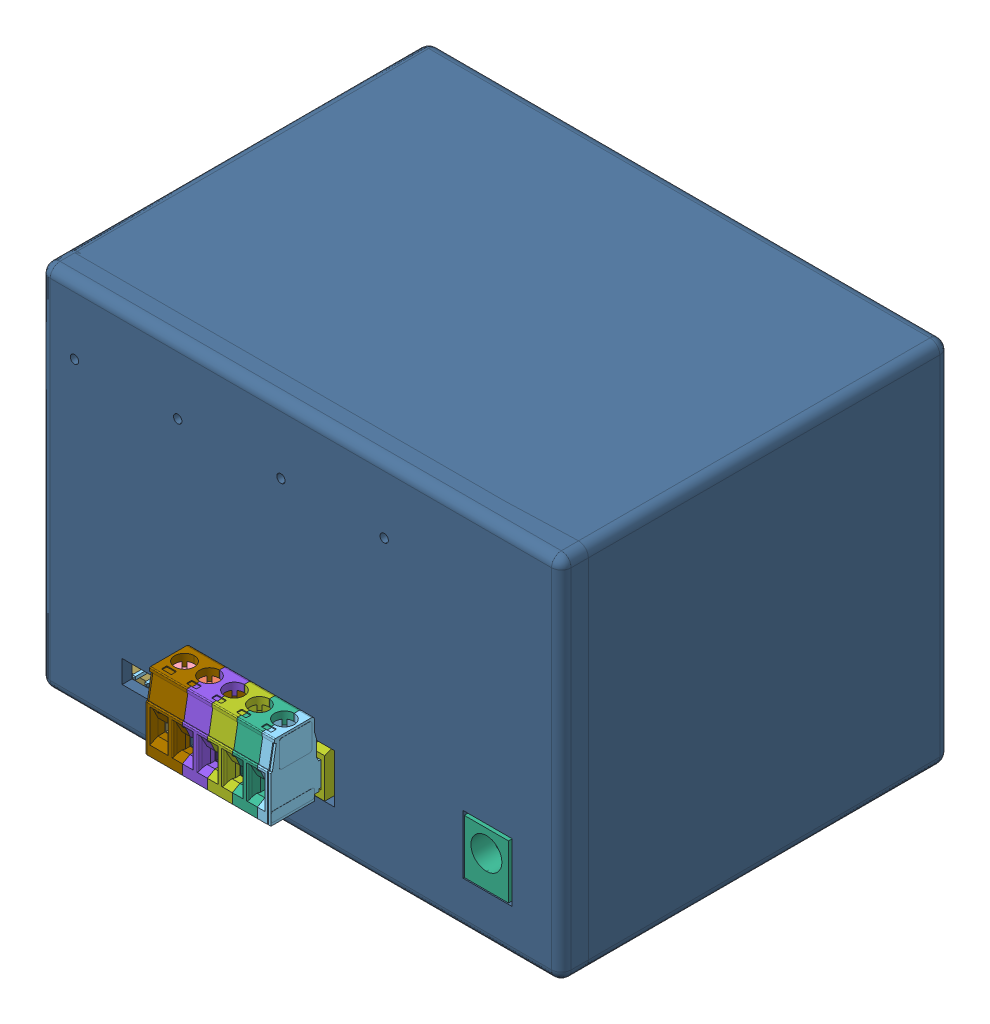
SolidWorks assembly scbs_array_enclosed_assy, configuration Default. Lengths in mm.
Overall size (106 74.85 90.17).
81 component instances, 28 part files, 2 mates.
Components (placement in the parent):
- scbs_array_pcba-1: scbs_array_pcba [Default] at (-110 -62.35 -69.591) x (1 0 0) z (0 1 0) size (91.35 87.17 67.03)
  - PinSocket_1x06_P2.54mm_Vertical-1: PinSocket_1x06_P2.54mm_Vertical [PinSocket_1x06_P2.54mm_Vertical] at (47 -65 1.65) size (2.54 15.24 10.1)
    - SOLID-1: SOLID [SOLID] at origin size (2.54 15.24 10.1)
  - scbs_pico-1: scbs_pico [scbs_pico] at (45.7 -102.3 87.35) x (0 0 -1) z (-1 0 0) size (60 60 13.4)
    - COMPOUND-1: COMPOUND [COMPOUND] at origin size (60 60 13.4)
  - Converter_DCDC_TRACO_TMR-xxxx_THT-1: Converter_DCDC_TRACO_TMR-xxxx_THT [Converter_DCDC_TRACO_TMR-xxxx_THT] at (33 -33 1.65) x (0 -1 0) z (0 0 1) size (21.8 9.2 15)
    - SOLID-0-1: SOLID-0 [SOLID-0] at origin size (21.8 9.2 15)
  - CP_Radial_D5.0mm_P2.50mm-1: CP_Radial_D5.0mm_P2.50mm [CP_Radial_D5.0mm_P2.50mm] at (61 -46 1.65) x (0 -1 0) z (0 0 1) size (6.13 6.52 7)
    - SOLID-1-1: SOLID-1 [SOLID-1] at origin size (6.13 6.52 7)
  - CP_Radial_D5.0mm_P2.50mm-2: CP_Radial_D5.0mm_P2.50mm [CP_Radial_D5.0mm_P2.50mm] at (103.5 -46 1.65) x (0 -1 0) z (0 0 1) size (6.13 6.52 7)
    - SOLID-1-1: SOLID-1 [SOLID-1] at origin size (6.13 6.52 7)
  - PinHeader_1x03_P2.54mm_Horizontal-1: PinHeader_1x03_P2.54mm_Horizontal [PinHeader_1x03_P2.54mm_Horizontal] at (36 -86 1.65) x (0 -1 0) z (0 0 1) size (10.36 7.62 5.54)
    - SOLID-2-1: SOLID-2 [SOLID-2] at origin size (10.36 7.62 5.54)
  - CP_Radial_D5.0mm_P2.50mm-3: CP_Radial_D5.0mm_P2.50mm [CP_Radial_D5.0mm_P2.50mm] at (61 -36 1.65) x (0 1 0) z (0 0 1) size (6.13 6.52 7)
    - SOLID-1-1: SOLID-1 [SOLID-1] at origin size (6.13 6.52 7)
  - CP_Radial_D5.0mm_P2.50mm-4: CP_Radial_D5.0mm_P2.50mm [CP_Radial_D5.0mm_P2.50mm] at (82 -46 1.65) x (0 -1 0) z (0 0 1) size (6.13 6.52 7)
    - SOLID-1-1: SOLID-1 [SOLID-1] at origin size (6.13 6.52 7)
  - Converter_DCDC_TRACO_TMR-xxxx_THT-2: Converter_DCDC_TRACO_TMR-xxxx_THT [Converter_DCDC_TRACO_TMR-xxxx_THT] at (96.5 -33 1.65) x (0 -1 0) z (0 0 1) size (21.8 9.2 15)
    - SOLID-0-1: SOLID-0 [SOLID-0] at origin size (21.8 9.2 15)
  - CP_Radial_D5.0mm_P2.50mm-5: CP_Radial_D5.0mm_P2.50mm [CP_Radial_D5.0mm_P2.50mm] at (40 -36 1.65) x (0 1 0) z (0 0 1) size (6.13 6.52 7)
    - SOLID-1-1: SOLID-1 [SOLID-1] at origin size (6.13 6.52 7)
  - SOFNG_DC005-T20-1: SOFNG_DC005-T20 [SOFNG_DC005-T20] at (103 -89 1.65) x (0 -1 0) z (-1 0 0) size (14.5 15.45 9.3)
    - COMPOUND-3-1: COMPOUND-3 [COMPOUND-3] at origin size (14.5 15.45 9.3)
  - PinSocket_1x06_P2.54mm_Vertical-2: PinSocket_1x06_P2.54mm_Vertical [PinSocket_1x06_P2.54mm_Vertical] at (68 -65 1.65) size (2.54 15.24 10.1)
    - SOLID-1: SOLID [SOLID] at origin size (2.54 15.24 10.1)
  - scbs_pico-2: scbs_pico [scbs_pico] at (66.7 -102.3 87.35) x (0 0 -1) z (-1 0 0) size (60 60 13.4)
    - COMPOUND-1: COMPOUND [COMPOUND] at origin size (60 60 13.4)
  - PhoenixContact_MSTBA_2,5_5-G-5,08_1x05_P5.08mm_Horizontal-1: PhoenixContact_MSTBA_2,5_5-G-5,08_1x05_P5.08mm_Horizontal [PhoenixContact_MSTBA_2,5_5-G-5,08_1x05_P5.08mm_Horizontal] at (47 -87 1.65) size (27.4 12 12.6)
    - SOLID-4-1: SOLID-4 [SOLID-4] at origin size (27.4 12 12.6)
  - PinSocket_1x06_P2.54mm_Vertical-3: PinSocket_1x06_P2.54mm_Vertical [PinSocket_1x06_P2.54mm_Vertical] at (26 -65 1.65) size (2.54 15.24 10.1)
    - SOLID-1: SOLID [SOLID] at origin size (2.54 15.24 10.1)
  - scbs_pico-3: scbs_pico [scbs_pico] at (24.7 -102.3 87.35) x (0 0 -1) z (-1 0 0) size (60 60 13.4)
    - COMPOUND-1: COMPOUND [COMPOUND] at origin size (60 60 13.4)
  - Converter_DCDC_TRACO_TMR-xxxx_THT-3: Converter_DCDC_TRACO_TMR-xxxx_THT [Converter_DCDC_TRACO_TMR-xxxx_THT] at (54 -33 1.65) x (0 -1 0) z (0 0 1) size (21.8 9.2 15)
    - SOLID-0-1: SOLID-0 [SOLID-0] at origin size (21.8 9.2 15)
  - CP_Radial_D5.0mm_P2.50mm-6: CP_Radial_D5.0mm_P2.50mm [CP_Radial_D5.0mm_P2.50mm] at (40 -46 1.65) x (0 -1 0) z (0 0 1) size (6.13 6.52 7)
    - SOLID-1-1: SOLID-1 [SOLID-1] at origin size (6.13 6.52 7)
  - PinSocket_1x06_P2.54mm_Vertical-4: PinSocket_1x06_P2.54mm_Vertical [PinSocket_1x06_P2.54mm_Vertical] at (89 -65 1.65) size (2.54 15.24 10.1)
    - SOLID-1: SOLID [SOLID] at origin size (2.54 15.24 10.1)
  - scbs_pico-4: scbs_pico [scbs_pico] at (87.7 -102.3 87.35) x (0 0 -1) z (-1 0 0) size (60 60 13.4)
    - COMPOUND-1: COMPOUND [COMPOUND] at origin size (60 60 13.4)
  - TO-220-3_Horizontal_TabDown-1: TO-220-3_Horizontal_TabDown [TO-220-3_Horizontal_TabDown] at (101 -78 1.65) size (10.25 19.74 10.78)
    - SOLID-5-1: SOLID-5 [SOLID-5] at origin size (10.25 19.74 10.78)
  - CP_Radial_D5.0mm_P2.50mm-7: CP_Radial_D5.0mm_P2.50mm [CP_Radial_D5.0mm_P2.50mm] at (82 -36 1.65) x (0 1 0) z (0 0 1) size (6.13 6.52 7)
    - SOLID-1-1: SOLID-1 [SOLID-1] at origin size (6.13 6.52 7)
  - Converter_DCDC_TRACO_TMR-xxxx_THT-4: Converter_DCDC_TRACO_TMR-xxxx_THT [Converter_DCDC_TRACO_TMR-xxxx_THT] at (75 -33 1.65) x (0 -1 0) z (0 0 1) size (21.8 9.2 15)
    - SOLID-0-1: SOLID-0 [SOLID-0] at origin size (21.8 9.2 15)
  - CP_Radial_D5.0mm_P2.50mm-8: CP_Radial_D5.0mm_P2.50mm [CP_Radial_D5.0mm_P2.50mm] at (103.5 -36 1.65) x (0 1 0) z (0 0 1) size (6.13 6.52 7)
    - SOLID-1-1: SOLID-1 [SOLID-1] at origin size (6.13 6.52 7)
  - R_0805_2012Metric-1: R_0805_2012Metric [R_0805_2012Metric] at (98 -70 -0.05) x (-1 0 0) z (0 0 -1) size (2 1.2 0.45)
    - SOLID-6-1: SOLID-6 [SOLID-6] at origin size (2 1.2 0.45)
  - C_0805_2012Metric-1: C_0805_2012Metric [C_0805_2012Metric] at (71 -50 -0.05) x (0 1 0) z (0 0 -1) size (2 1.25 1.25)
    - SOLID-7-1: SOLID-7 [SOLID-7] at origin size (2 1.25 1.25)
  - D_MELF-1: D_MELF [D_MELF] at (103.54 -73.77 -0.05) x (-1 0 0) z (0 0 -1) size (5.8 2.2 2.2)
    - SOLID-8-1: SOLID-8 [SOLID-8] at origin size (5.8 2.2 2.2)
  - C_0805_2012Metric-2: C_0805_2012Metric [C_0805_2012Metric] at (49.4 -50 -0.05) x (0 1 0) z (0 0 -1) size (2 1.25 1.25)
    - SOLID-7-1: SOLID-7 [SOLID-7] at origin size (2 1.25 1.25)
  - R_0805_2012Metric-2: R_0805_2012Metric [R_0805_2012Metric] at (94 -70 -0.05) x (0 1 0) z (0 0 -1) size (2 1.2 0.45)
    - SOLID-6-1: SOLID-6 [SOLID-6] at origin size (2 1.2 0.45)
  - C_0805_2012Metric-3: C_0805_2012Metric [C_0805_2012Metric] at (29 -50 -0.05) x (0 1 0) z (0 0 -1) size (2 1.25 1.25)
    - SOLID-7-1: SOLID-7 [SOLID-7] at origin size (2 1.25 1.25)
  - C_0805_2012Metric-4: C_0805_2012Metric [C_0805_2012Metric] at (92.5 -50 -0.05) x (0 1 0) z (0 0 -1) size (2 1.25 1.25)
    - SOLID-7-1: SOLID-7 [SOLID-7] at origin size (2 1.25 1.25)
  - scbs_array PCB-1: scbs_array PCB [scbs_array PCB] at origin size (90 74 1.6)
  - pxc_1757048_06_MSTB-2-5-5-ST-5-08_3D-1: pxc_1757048_06_MSTB-2-5-5-ST-5-08_3D [pxc_1757048_06_MSTB-2-5-5-ST-5-08_3D] at (44.46 -106.94 1.705) size (25.46 18.3 15)
    - 2022_06_08_09_32_02_0871-1: 2022_06_08_09_32_02_0871 [2022_06_08_09_32_02_0871] at origin size (3.8 5 6.8)
    - 2022_06_08_09_32_02_0840-1: 2022_06_08_09_32_02_0840 [2022_06_08_09_32_02_0840] at origin size (3.82 3.82 6.8)
    - 2022_06_08_09_32_02_0809-1: 2022_06_08_09_32_02_0809 [2022_06_08_09_32_02_0809] at origin size (3.8 5 6.8)
    - 2022_06_08_09_32_02_0778-1: 2022_06_08_09_32_02_0778 [2022_06_08_09_32_02_0778] at origin size (3.82 3.82 6.8)
    - 2022_06_08_09_32_02_0746-1: 2022_06_08_09_32_02_0746 [2022_06_08_09_32_02_0746] at origin size (3.8 5 6.8)
    - 2022_06_08_09_32_02_0715-1: 2022_06_08_09_32_02_0715 [2022_06_08_09_32_02_0715] at origin size (3.82 3.82 6.8)
    - 2022_06_08_09_32_02_0684-1: 2022_06_08_09_32_02_0684 [2022_06_08_09_32_02_0684] at origin size (3.8 5 6.8)
    - 2022_06_08_09_32_02_0653-1: 2022_06_08_09_32_02_0653 [2022_06_08_09_32_02_0653] at origin size (3.82 3.82 6.8)
    - 2022_06_08_09_32_02_0635-1: 2022_06_08_09_32_02_0635 [2022_06_08_09_32_02_0635] at origin size (3.8 5 6.8)
    - 2022_06_08_09_32_02_0631-1: 2022_06_08_09_32_02_0631 [2022_06_08_09_32_02_0631] at origin size (3.82 3.82 6.8)
    - 2022_06_08_09_32_02_0627-1: 2022_06_08_09_32_02_0627 [2022_06_08_09_32_02_0627] at origin size (5.11 18.3 15)
    - 2022_06_08_09_32_02_0623-1: 2022_06_08_09_32_02_0623 [2022_06_08_09_32_02_0623] at origin size (5.08 18.3 15)
    - 2022_06_08_09_32_02_0619-1: 2022_06_08_09_32_02_0619 [2022_06_08_09_32_02_0619] at origin size (5.08 18.3 15)
    - 2022_06_08_09_32_02_0615-1: 2022_06_08_09_32_02_0615 [2022_06_08_09_32_02_0615] at origin size (5.08 18.3 15)
    - 2022_06_08_09_32_02_0611-1: 2022_06_08_09_32_02_0611 [2022_06_08_09_32_02_0611] at origin size (7.65 18.3 15)
- enclosure_back_shell^scbs_array_enclosed_assy-1: enclosure_back_shell^scbs_array_enclosed_assy [Default] at origin size (106 74.85 79) (virtual)
Mates (geometry in assembly coordinates):
- Coincident1: coincident aligned: plane of scbs_array_pcba-1/scbs_array PCB-1 through (0 -62.35 -49.591) normal (1 0 0)
- Coincident2: coincident aligned: plane of scbs_array_pcba-1/scbs_pico-2/COMPOUND-1 through (-43.3 0 -47.291) normal (0 1 0)
